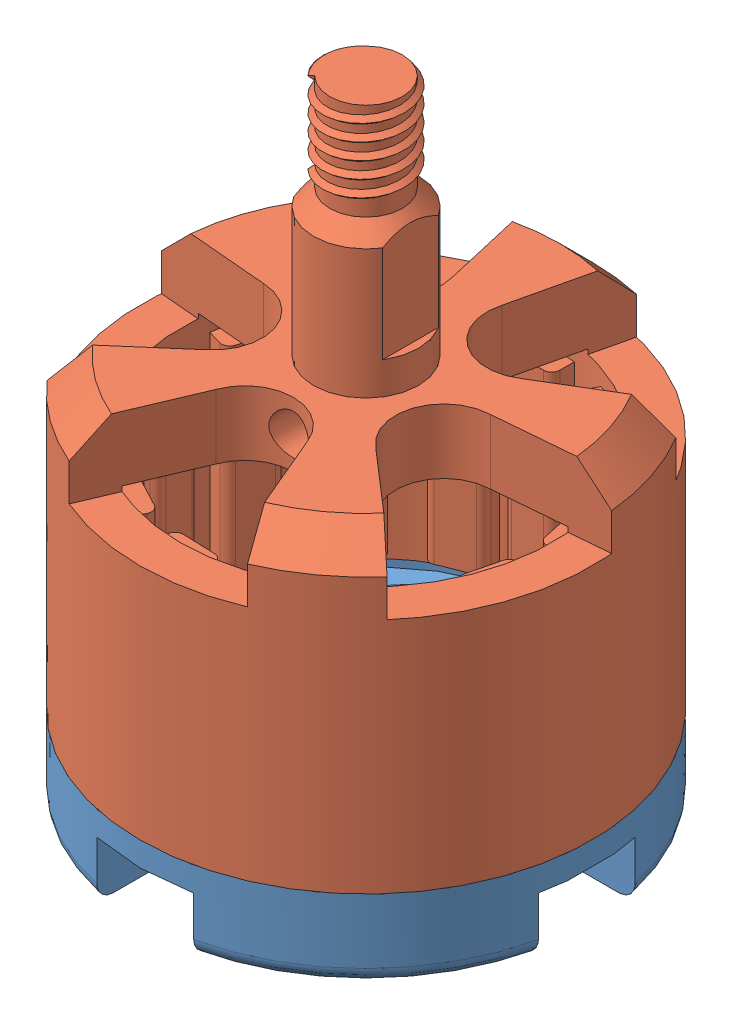
SolidWorks assembly Assem1, configuration Varsayılan. Lengths in mm.
Overall size (28 39.31 28).
2 component instances, 2 part files, 1 mates.
Components (placement in the parent):
- Moteur brushless - Base-1: Moteur brushless - Base [Défaut] at (0.6547 -3.0153 28) size (28 5.06 28)
- Part7-1: Part7 [Varsayılan] at (0.6547 1.9847 28) size (28 34.24 28)
Mates (geometry in assembly coordinates):
- Çakışık1: coincident aligned: circle of Moteur brushless - Base-1; circle of Part7-1
